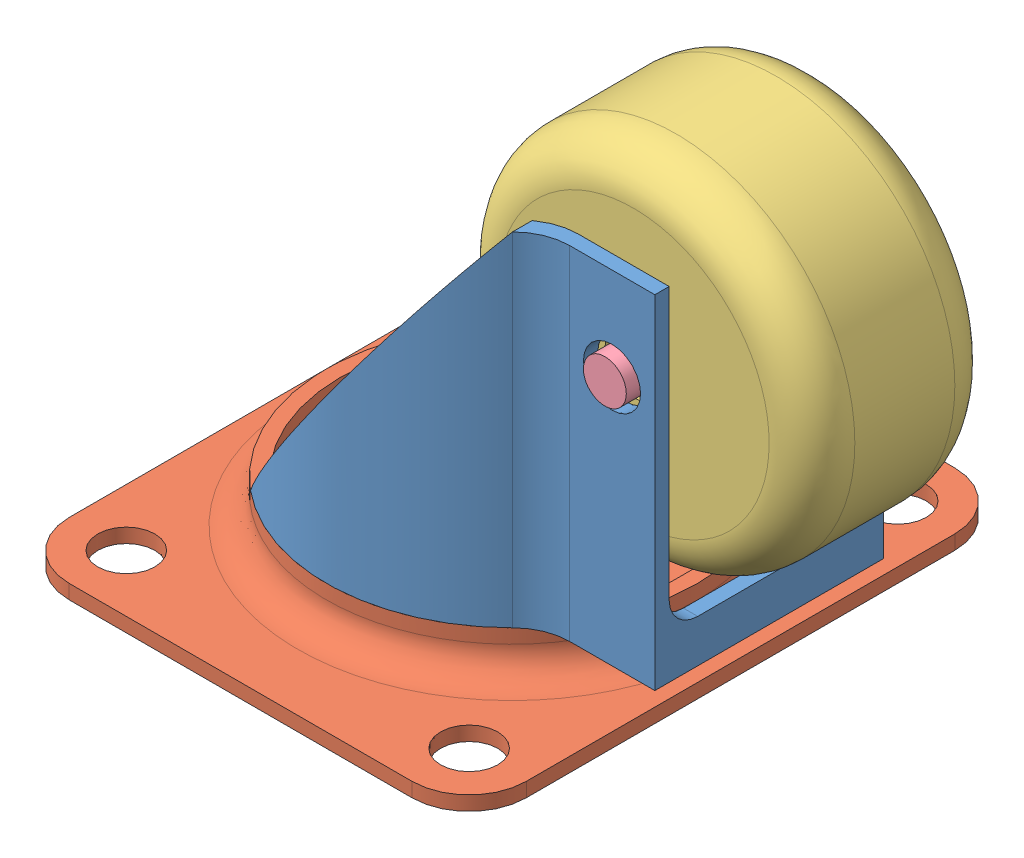
SolidWorks assembly CastorWheelAssembly, configuration Default. Lengths in mm.
Overall size (43.5 34 38).
4 component instances, 4 part files, 7 mates.
Components (placement in the parent):
- attachment-1: attachment [Default] at (4.8041 5.932 24.3372) size (26.28 24 26)
- Plate-1: Plate [Default] at (4.8041 2.932 24.3372) x (0 0 1) z (1 0 0) size (38 4 32)
- CastorWheel-1: CastorWheel [Default] at (19.8041 23.432 24.3372) size (25 25 13)
- Pin-1: Pin [Default] at (19.8041 23.432 16.8372) x (0 0 1) z (-1 0 0) size (16 3 3)
Mates (geometry in assembly coordinates):
- Coincident1: coincident anti-aligned: plane of attachment-1 through (4.8041 5.932 24.3372) normal (0 -1 0); plane of Plate-1 through (4.8041 5.932 24.3372) normal (0 1 0)
- Concentric1: concentric aligned: circle of attachment-1; circle of Plate-1
- Parallel1: parallel aligned: plane of attachment-1 through (22.8041 29.932 32.3372) normal (0 0 1); plane of Plate-1 through (20.8041 1.932 43.3372) normal (0 0 1)
- Concentric2: concentric aligned: cylinder of attachment-1 through (19.8041 23.432 11.3372) axis (0 0 1) radius 2; cylinder of CastorWheel-1 through (19.8041 23.432 17.8372) axis (0 0 1) radius 2
- Width1: width anti-aligned: plane of attachment-1 through (21.8041 29.932 17.3372) normal (0 0 1); plane of CastorWheel-1 through (21.8041 29.932 31.3372) normal (0 0 -1); plane of attachment-1 through (19.8041 23.432 17.8372) normal (0 0 -1); plane of CastorWheel-1 through (19.8041 23.432 30.8372) normal (0 0 1)
- Concentric3: concentric anti-aligned: cylinder of CastorWheel-1 through (19.8041 23.432 17.8372) axis (0 0 1) radius 2; cylinder of Pin-1 through (19.8041 23.432 32.8372) axis (0 0 -1) radius 1.5
- Distance1: distance = 0.5 mm aligned: plane of attachment-1 through (22.8041 29.932 32.3372) normal (0 0 1); plane of Pin-1 through (19.8041 23.432 32.8372) normal (0 0 1)
